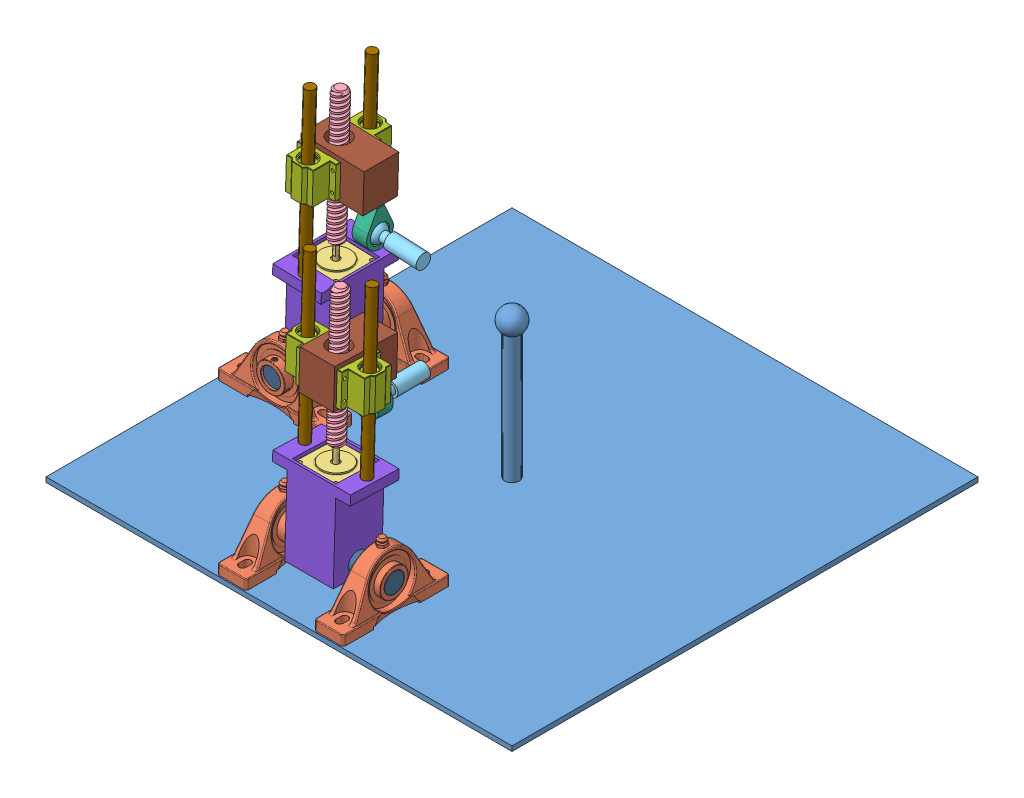
SolidWorks assembly vertical_Assem rev4, configuration Default. Lengths in mm.
Overall size (609.6 357.31 609.6).
28 component instances, 12 part files, 76 mates.
Components (placement in the parent):
- Bottom Platform rev2-1: Bottom Platform rev2 [Default] at origin size (609.6 200.03 609.6)
- 7728T560_MOUNTED BALL BEARING WITH CAST IRON HOUSING-1: 7728T560_MOUNTED BALL BEARING WITH CAST IRON HOUSING [7728T56] at (-63.5 42.8625 233.3625) x (0 0 -1) z (1 0 0) size (139.7 80.96 38.1)
- 7728T560_MOUNTED BALL BEARING WITH CAST IRON HOUSING-2: 7728T560_MOUNTED BALL BEARING WITH CAST IRON HOUSING [7728T56] at (-233.3625 42.8625 63.5) size (139.7 80.96 38.1)
- 7728T560_MOUNTED BALL BEARING WITH CAST IRON HOUSING-3: 7728T560_MOUNTED BALL BEARING WITH CAST IRON HOUSING [7728T56] at (-233.3625 42.8625 -63.5) size (139.7 80.96 38.1)
- 7728T560_MOUNTED BALL BEARING WITH CAST IRON HOUSING-4: 7728T560_MOUNTED BALL BEARING WITH CAST IRON HOUSING [7728T56] at (63.5 42.8625 233.3625) x (0 0 1) z (-1 0 0) size (139.7 80.96 38.1)
- 6627T540_POSITION-CONTROL DC MOTOR-2: 6627T540_POSITION-CONTROL DC MOTOR [6627T54] at (0 137.4326 230.4477) x (1 0 0) z (0 0.999525 -0.030807) size (57.15 58.17 99.31)
- 6627T540_POSITION-CONTROL DC MOTOR-3: 6627T540_POSITION-CONTROL DC MOTOR [6627T54] at (-230.4293 137.432 0) x (0 0 -1) z (0.031002 0.999519 0) size (57.15 58.17 99.31)
- 5966K221_BALL SCREW-3: 5966K221_BALL SCREW [5966K221] at (-229.7914 157.9961 0) x (0.970979 -0.030116 -0.237261) z (-0.031002 -0.999519 0) size (20.38 19.09 183.37)
- 5966K221_BALL SCREW-4: 5966K221_BALL SCREW [5966K221] at (0 157.9968 229.8138) x (0.271467 0.029651 0.961991) z (0 -0.999525 0.030807) size (20.38 19.09 183.37)
- top_Platform rev2-1: top_Platform rev2 [Default] at (0.7095 200.0079 0.2014) x (-0.999001 0.044698 -0.000225) z (-0.000791 -0.012664 0.999919) size (317.5 25.4 317.5) (hidden)
- ball-2: ball [Default] at (0.0499 185.85 116.2359) x (0.999641 -0.0268 0.000452) z (-0.026792 -0.999561 -0.01268) size (25.4 75.77 25.4)
- hole-1: hole [Default] at (0 258.8925 180.1999) x (0 0.030807 0.999525) z (1 0 0) size (19.05 91.29 35.03)
- ball-3: ball [Default] at (-115.947 192.5157 0.0142) x (0.040283 0.898119 -0.437904) z (0.019372 0.437476 0.899022) size (25.4 75.77 25.4)
- hole-2: hole [Default] at (-179.8387 269.1761 0) x (-0.999519 0.031002 0) z (0 0 1) size (19.05 91.29 35.03)
- 9338T100_MOUNTED LINEAR BALL BRNG-1: 9338T100_MOUNTED LINEAR BALL BRNG [9338T1] at (39.0525 243.1877 227.1881) x (0 -0.030807 -0.999525) z (0 0.999525 -0.030807) size (50.8 31.75 42.86)
- 9338T100_MOUNTED LINEAR BALL BRNG-2: 9338T100_MOUNTED LINEAR BALL BRNG [9338T1] at (-39.116 243.1887 227.2198) x (0 0.030807 0.999525) z (0 0.999525 -0.030807) size (50.8 31.75 42.86)
- 9338T100_MOUNTED LINEAR BALL BRNG-3: 9338T100_MOUNTED LINEAR BALL BRNG [9338T1] at (-226.8616 253.4814 -39.116) x (-0.999519 0.031002 0) z (0.031002 0.999519 0) size (50.8 31.75 42.86)
- 9338T100_MOUNTED LINEAR BALL BRNG-4: 9338T100_MOUNTED LINEAR BALL BRNG [9338T1] at (-226.8298 253.4804 39.0525) x (0.999519 -0.031002 0) z (0.031002 0.999519 0) size (50.8 31.75 42.86)
- motor mount-2: motor mount [Default] at (-265.5894 27.9794 -31.75) x (0 0 1) z (-0.999519 0.031002 0) size (101.6 114.3 63.5)
- motor mount-3: motor mount [Default] at (-31.75 27.9732 265.5865) x (1 0 0) z (0 0.030807 0.999525) size (101.6 114.3 63.5)
- linear bar-1: linear bar [Default] at (-230.8615 128.5512 -40.64) x (0.999519 -0.031002 0.000002) z (-0.000002 0 1) size (12.7 228.6 12.7)
- linear bar-2: linear bar [Default] at (40.64 128.5468 230.7215) x (-0.564697 -0.025425 -0.824906) z (0.825298 -0.017397 -0.564429) size (12.7 228.6 12.7)
- linear bar-3: linear bar [Default] at (-40.64 128.5516 230.8782) x (-0.912321 -0.012615 -0.409281) z (0.409475 -0.028106 -0.911888) size (12.7 228.6 12.7)
- linear bar-4: linear bar [Default] at (-230.7049 128.5463 40.64) x (0.951171 -0.029502 0.307253) z (-0.307105 0.009525 0.951628) size (12.7 228.6 12.7)
- horizontal bar-1: horizontal bar [Default] at (-79.375 42.8625 233.3625) size (158.75 25.4 25.4)
- horizontal bar-2: horizontal bar [Default] at (-233.3625 42.8625 -79.375) x (0 0 1) z (-1 0 0) size (158.75 25.4 25.4)
- screw_attach rev3-1: screw_attach rev3 [Default] at (-255.4169 228.9549 -23.241) x (0.999519 -0.031002 0) z (0 0 1) size (82.55 50.8 45.47)
- screw_attach rev3-2: screw_attach rev3 [Default] at (-23.241 218.6566 255.7704) x (0 -0.030807 -0.999525) z (1 0 0) size (82.55 50.8 45.47)
Mates (geometry in assembly coordinates):
- Coincident1: coincident anti-aligned: plane of Bottom Platform rev2-1 through (0 6.35 0) normal (0 1 0); plane of 7728T560_MOUNTED BALL BEARING WITH CAST IRON HOUSING-1 through (-44.45 6.35 203.2) normal (0 -1 0)
- Tangent3: tangent anti-aligned: cylinder of Bottom Platform rev2-1 through (-63.5 6.35 180.975) axis (0 1 0) radius 4.7625; plane of 7728T560_MOUNTED BALL BEARING WITH CAST IRON HOUSING-1 through (-58.7375 6.35 288.925) normal (-1 0 0)
- Tangent5: tangent anti-aligned: cylinder of Bottom Platform rev2-1 through (-63.5 6.35 285.75) axis (0 1 0) radius 4.7625; plane of 7728T560_MOUNTED BALL BEARING WITH CAST IRON HOUSING-1 through (-58.7375 6.35 288.925) normal (-1 0 0)
- Coincident3: coincident: cylinder of Bottom Platform rev2-1 through (-63.5 6.35 180.975) axis (0 1 0) radius 4.7625; moEndPointRef_w of 7728T560_MOUNTED BALL BEARING WITH CAST IRON HOUSING-1
- Coincident4: coincident anti-aligned: plane of Bottom Platform rev2-1 through (0 6.35 0) normal (0 1 0); plane of 7728T560_MOUNTED BALL BEARING WITH CAST IRON HOUSING-2 through (-303.2125 6.35 82.55) normal (0 -1 0)
- Coincident5: coincident anti-aligned: plane of Bottom Platform rev2-1 through (0 6.35 0) normal (0 1 0); plane of 7728T560_MOUNTED BALL BEARING WITH CAST IRON HOUSING-4 through (44.45 6.35 163.5125) normal (0 -1 0)
- Coincident6: coincident anti-aligned: plane of Bottom Platform rev2-1 through (0 6.35 0) normal (0 1 0); plane of 7728T560_MOUNTED BALL BEARING WITH CAST IRON HOUSING-3 through (-303.2125 6.35 -44.45) normal (0 -1 0)
- Tangent6: tangent anti-aligned: cylinder of Bottom Platform rev2-1 through (63.5 6.35 285.75) axis (0 1 0) radius 4.7625; plane of 7728T560_MOUNTED BALL BEARING WITH CAST IRON HOUSING-4 through (68.2625 6.35 282.575) normal (-1 0 0)
- Tangent7: tangent anti-aligned: cylinder of Bottom Platform rev2-1 through (63.5 6.35 180.975) axis (0 1 0) radius 4.7625; plane of 7728T560_MOUNTED BALL BEARING WITH CAST IRON HOUSING-4 through (68.2625 6.35 177.8) normal (-1 0 0)
- Coincident7: coincident: cylinder of Bottom Platform rev2-1 through (63.5 6.35 180.975) axis (0 1 0) radius 4.7625; moEndPointRef_w of 7728T560_MOUNTED BALL BEARING WITH CAST IRON HOUSING-4
- Tangent8: tangent anti-aligned: cylinder of Bottom Platform rev2-1 through (-180.975 6.35 63.5) axis (0 1 0) radius 4.7625; plane of 7728T560_MOUNTED BALL BEARING WITH CAST IRON HOUSING-2 through (-184.15 6.35 58.7375) normal (0 0 1)
- Tangent9: tangent anti-aligned: cylinder of Bottom Platform rev2-1 through (-285.75 6.35 63.5) axis (0 1 0) radius 4.7625; plane of 7728T560_MOUNTED BALL BEARING WITH CAST IRON HOUSING-2 through (-288.925 6.35 58.7375) normal (0 0 1)
- Coincident8: coincident: cylinder of Bottom Platform rev2-1 through (-180.975 6.35 63.5) axis (0 1 0) radius 4.7625; moEndPointRef_w of 7728T560_MOUNTED BALL BEARING WITH CAST IRON HOUSING-2
- Tangent10: tangent anti-aligned: cylinder of Bottom Platform rev2-1 through (-180.975 6.35 -63.5) axis (0 1 0) radius 4.7625; plane of 7728T560_MOUNTED BALL BEARING WITH CAST IRON HOUSING-3 through (-184.15 6.35 -68.2625) normal (0 0 1)
- Tangent11: tangent anti-aligned: cylinder of Bottom Platform rev2-1 through (-285.75 6.35 -63.5) axis (0 1 0) radius 4.7625; plane of 7728T560_MOUNTED BALL BEARING WITH CAST IRON HOUSING-3 through (-288.925 6.35 -68.2625) normal (0 0 1)
- Coincident9: coincident: cylinder of Bottom Platform rev2-1 through (-285.75 6.35 -63.5) axis (0 1 0) radius 4.7625; moEndPointRef_w of 7728T560_MOUNTED BALL BEARING WITH CAST IRON HOUSING-3
- Coincident12: coincident: moEndPointRef_w of 6627T540_POSITION-CONTROL DC MOTOR-3; plane of assembly
- Coincident13: coincident: moEndPointRef_w of 6627T540_POSITION-CONTROL DC MOTOR-2; plane of assembly
- Coincident16: coincident anti-aligned: plane of 6627T540_POSITION-CONTROL DC MOTOR-3 through (-232.9649 158.0946 0) normal (0.031002 0.999519 0); plane of 5966K221_BALL SCREW-3 through (-229.7914 157.9961 0) normal (-0.031002 -0.999519 0)
- Concentric5: concentric anti-aligned: cylinder of 6627T540_POSITION-CONTROL DC MOTOR-3 through (-229.7914 157.9961 0) axis (0.031002 0.999519 0) radius 3.175; cylinder of 5966K221_BALL SCREW-3 through (-224.2793 335.7107 0) axis (-0.031002 -0.999519 0) radius 9.525
- Concentric6: concentric anti-aligned: cylinder of 6627T540_POSITION-CONTROL DC MOTOR-2 through (0 157.9968 229.8138) axis (0 0.999525 -0.030807) radius 3.175; cylinder of 5966K221_BALL SCREW-4 through (0 335.7124 224.3363) axis (0 -0.999525 0.030807) radius 9.525
- Coincident17: coincident anti-aligned: plane of 6627T540_POSITION-CONTROL DC MOTOR-2 through (0 157.899 226.6403) normal (0 0.999525 -0.030807); plane of 5966K221_BALL SCREW-4 through (0 157.9968 229.8138) normal (0 -0.999525 0.030807)
- Concentric18: concentric anti-aligned: cylinder of top_Platform rev2-1 through (0.0162 185.3112 158.7775) axis (-0.000791 -0.012664 0.999919) radius 9.525; cylinder of ball-2 through (0.0162 185.3112 158.7775) axis (0.000791 0.012664 -0.999919) radius 9.525
- Coincident31: coincident aligned: circle of top_Platform rev2-1; circle of ball-2
- Tangent12: tangent aligned: sphere of ball-2; cylinder of hole-1 through (0 184.8557 172.9524) axis (0 0.030807 0.999525) radius 12.7
- Concentric20: concentric anti-aligned: cylinder of top_Platform rev2-1 through (-158.4494 194.4173 0.0046) axis (-0.999001 0.044698 -0.000225) radius 9.525; cylinder of ball-3 through (-158.4494 194.4173 0.0046) axis (0.999001 -0.044698 0.000225) radius 9.525
- Coincident35: coincident aligned: plane of top_Platform rev2-1 through (-159.1427 179.7207 158.5807) normal (-0.999001 0.044698 -0.000225); plane of ball-3 through (-158.4494 194.4173 0.0046) normal (-0.999001 0.044698 -0.000225)
- Tangent13: tangent aligned: sphere of ball-3; cylinder of hole-2 through (-172.6055 195.1378 0) axis (-0.999519 0.031002 0) radius 12.7
- Parallel5: parallel anti-aligned: plane of Bottom Platform rev2-1 through (0 6.35 0) normal (0 1 0); plane of top_Platform rev2-1
- Tangent16: tangent aligned: sphere of Bottom Platform rev2-1; cylinder of top_Platform rev2-1 through (-0.4257 174.6353 -0.1208) axis (0.044691 0.99892 0.012687) radius 15.875
- Tangent18: tangent aligned: sphere of Bottom Platform rev2-1; plane of top_Platform rev2-1 through (0.7095 200.0079 0.2014) normal (0.044691 0.99892 0.012687)
- Coincident50: coincident anti-aligned: plane of 6627T540_POSITION-CONTROL DC MOTOR-3 through (-217.79 58.2621 25.019) normal (-0.031002 -0.999519 0); plane of motor mount-2 through (-264.6051 59.7142 -31.75) normal (0.031002 0.999519 0)
- Coincident51: coincident anti-aligned: plane of 6627T540_POSITION-CONTROL DC MOTOR-3 through (-205.199 131.567 -28.575) normal (0 0 -1); plane of motor mount-2 through (-258.8724 142.1261 -28.575) normal (0 0 1)
- Coincident52: coincident anti-aligned: plane of 6627T540_POSITION-CONTROL DC MOTOR-3 through (-259.148 133.2403 -25.4) normal (-0.999519 0.031002 0); plane of motor mount-2 through (-258.8724 142.1261 -28.575) normal (0.999519 -0.031002 0)
- Coincident53: coincident anti-aligned: plane of 6627T540_POSITION-CONTROL DC MOTOR-2 through (-25.019 59.1948 247.9539) normal (0 -0.999525 0.030807); plane of motor mount-3 through (-31.75 59.7081 264.6084) normal (0 0.999525 -0.030807)
- Coincident54: coincident anti-aligned: plane of 6627T540_POSITION-CONTROL DC MOTOR-2 through (25.4 131.4747 202.0427) normal (0 -0.030807 -0.999525); plane of motor mount-3 through (-28.575 140.3605 201.7688) normal (0 0.030807 0.999525)
- Coincident55: coincident anti-aligned: plane of 6627T540_POSITION-CONTROL DC MOTOR-2 through (28.575 133.1375 255.9921) normal (1 0 0); plane of motor mount-3 through (28.575 142.1211 258.8917) normal (-1 0 0)
- Coincident56: coincident aligned: plane of motor mount-2 through (-262.4396 129.5306 -50.8) normal (-0.031002 -0.999519 0); plane of linear bar-1 through (-230.8615 128.5512 -40.64) normal (-0.031002 -0.999519 0)
- Concentric43: concentric anti-aligned: cylinder of motor mount-2 through (-230.4678 141.245 -40.64) axis (0.031002 0.999519 0) radius 6.35; cylinder of linear bar-1 through (-223.7745 357.0413 -40.64) axis (-0.031002 -0.999519 0) radius 6.35
- Concentric44: concentric anti-aligned: cylinder of motor mount-2 through (-230.3112 141.2402 40.64) axis (0.031002 0.999519 0) radius 6.35; cylinder of linear bar-4 through (-223.6179 357.0364 40.64) axis (-0.031002 -0.999519 0) radius 6.35
- Coincident57: coincident aligned: plane of motor mount-2 through (-262.4396 129.5306 50.8) normal (-0.031002 -0.999519 0); plane of linear bar-4 through (-230.7049 128.5463 40.64) normal (-0.031002 -0.999519 0)
- Concentric45: concentric anti-aligned: cylinder of motor mount-3 through (-40.64 141.2456 230.4869) axis (0 0.999525 -0.030807) radius 6.35; cylinder of linear bar-3 through (-40.64 357.0431 223.8356) axis (0 -0.999525 0.030807) radius 6.35
- Concentric46: concentric anti-aligned: cylinder of motor mount-3 through (40.64 141.2408 230.3303) axis (0 0.999525 -0.030807) radius 6.35; cylinder of linear bar-2 through (40.64 357.0383 223.679) axis (0 -0.999525 0.030807) radius 6.35
- Coincident58: coincident aligned: plane of motor mount-3 through (-50.8 129.5249 262.4565) normal (0 -0.999525 0.030807); plane of linear bar-3 through (-40.64 128.5516 230.8782) normal (0 -0.999525 0.030807)
- Coincident59: coincident aligned: plane of motor mount-3 through (50.8 129.5249 262.4565) normal (0 -0.999525 0.030807); plane of linear bar-2 through (40.64 128.5468 230.7215) normal (0 -0.999525 0.030807)
- Concentric47: concentric anti-aligned: cylinder of 9338T100_MOUNTED LINEAR BALL BRNG-1 through (40.64 221.7666 227.8483) axis (0 0.999525 -0.030807) radius 6.35; cylinder of linear bar-2 through (40.64 357.0383 223.679) axis (0 -0.999525 0.030807) radius 6.35
- Concentric48: concentric anti-aligned: cylinder of 9338T100_MOUNTED LINEAR BALL BRNG-4 through (-227.4943 232.0594 40.64) axis (0.031002 0.999519 0) radius 6.35; cylinder of linear bar-4 through (-223.6179 357.0364 40.64) axis (-0.031002 -0.999519 0) radius 6.35
- Coincident60: coincident aligned: plane of 7728T560_MOUNTED BALL BEARING WITH CAST IRON HOUSING-1 through (-79.375 42.8625 233.3625) normal (-1 0 0); plane of horizontal bar-1 through (-79.375 42.8625 233.3625) normal (-1 0 0)
- Concentric51: concentric anti-aligned: cylinder of 7728T560_MOUNTED BALL BEARING WITH CAST IRON HOUSING-1 through (-79.375 42.8625 233.3625) axis (1 0 0) radius 12.7025; cylinder of horizontal bar-1 through (79.375 42.8625 233.3625) axis (-1 0 0) radius 12.7
- Coincident61: coincident aligned: plane of 7728T560_MOUNTED BALL BEARING WITH CAST IRON HOUSING-3 through (-233.3625 42.8625 -79.375) normal (0 0 -1); plane of horizontal bar-2 through (-233.3625 42.8625 -79.375) normal (0 0 -1)
- Concentric52: concentric anti-aligned: cylinder of 7728T560_MOUNTED BALL BEARING WITH CAST IRON HOUSING-3 through (-233.3625 42.8625 -79.375) axis (0 0 1) radius 12.7025; cylinder of horizontal bar-2 through (-233.3625 42.8625 79.375) axis (0 0 -1) radius 12.7
- Concentric54: concentric anti-aligned: cylinder of motor mount-2 through (-233.3625 42.8625 31.75) axis (0 0 1) radius 12.7; cylinder of horizontal bar-2 through (-233.3625 42.8625 79.375) axis (0 0 -1) radius 12.7
- Concentric56: concentric anti-aligned: cylinder of motor mount-3 through (31.75 42.8625 233.3625) axis (1 0 0) radius 12.7; cylinder of horizontal bar-1 through (79.375 42.8625 233.3625) axis (-1 0 0) radius 12.7
- Screw1: screw = 25.4 mm anti-aligned: cylinder of 5966K221_BALL SCREW-3 through (-224.2793 335.7107 0) axis (-0.031002 -0.999519 0) radius 9.525; cylinder of screw_attach rev3-1 through (-227.6173 228.0926 0) axis (0.031002 0.999519 0) radius 14
- Coincident62: coincident anti-aligned: plane of 9338T100_MOUNTED LINEAR BALL BRNG-3 through (-200.8094 274.1149 -23.241) normal (0 0 1); plane of screw_attach rev3-1 through (-255.4169 228.9549 -23.241) normal (0 0 -1)
- Concentric59: concentric anti-aligned: cylinder of 9338T100_MOUNTED LINEAR BALL BRNG-3 through (-205.0469 265.5109 -35.2037) axis (0 0 1) radius 1.9844; cylinder of screw_attach rev3-1 through (-205.0469 265.5109 -23.241) axis (0 0 -1) radius 1.9844
- Concentric60: concentric anti-aligned: cylinder of 9338T100_MOUNTED LINEAR BALL BRNG-3 through (-247.8888 266.8397 -35.2037) axis (0 0 1) radius 1.9844; cylinder of screw_attach rev3-1 through (-247.8888 266.8397 -23.241) axis (0 0 -1) radius 1.9844
- Parallel10: parallel aligned: plane of motor mount-2 through (-264.6051 59.7142 -31.75) normal (-0.999519 0.031002 0); plane of screw_attach rev3-1 through (-255.4169 228.9549 22.225) normal (-0.999519 0.031002 0)
- Parallel12: parallel anti-aligned: plane of 9338T100_MOUNTED LINEAR BALL BRNG-4 through (-251.5532 275.6888 23.1775) normal (0 0 -1); plane of screw_attach rev3-1 through (-255.4169 228.9549 22.225) normal (0 0 1)
- Screw2: screw = 25.4 mm anti-aligned: cylinder of 5966K221_BALL SCREW-4 through (0 335.7124 224.3363) axis (0 -0.999525 0.030807) radius 9.525; cylinder of screw_attach rev3-2 through (0 217.7997 227.9706) axis (0 0.999525 -0.030807) radius 14
- Parallel15: parallel aligned: plane of motor mount-3 through (-31.75 59.7081 264.6084) normal (0 0.030807 0.999525); plane of screw_attach rev3-2 through (22.225 218.6566 255.7704) normal (0 0.030807 0.999525)
- Parallel19: parallel anti-aligned: plane of 9338T100_MOUNTED LINEAR BALL BRNG-1 through (23.1775 263.8262 201.1399) normal (-1 0 0); plane of screw_attach rev3-2 through (22.225 218.6566 255.7704) normal (1 0 0)
- Parallel21: parallel aligned: plane of hole-1 through (0 185.4425 191.9933) normal (0 0.030807 0.999525); plane of motor mount-3 through (-31.75 59.7081 264.6084) normal (0 0.030807 0.999525)
- Tangent24: tangent aligned: sphere of ball-2; plane of hole-1 through (0 185.4425 191.9933) normal (0 0.030807 0.999525)
- Concentric78: concentric anti-aligned: cylinder of hole-2 through (-181.1576 226.6516 0) axis (0.031002 0.999519 0) radius 4.7625; cylinder of screw_attach rev3-1 through (-181.1576 226.6516 0) axis (-0.031002 -0.999519 0) radius 4.2164
- Coincident76: coincident anti-aligned: plane of hole-2 through (-171.6372 226.3563 4.7625) normal (0.031002 0.999519 0); plane of screw_attach rev3-1 through (-172.9066 226.3957 22.225) normal (-0.031002 -0.999519 0)
- Parallel22: parallel aligned: plane of hole-2 through (-191.6463 195.7284 0) normal (-0.999519 0.031002 0); plane of motor mount-2 through (-264.6051 59.7142 -31.75) normal (-0.999519 0.031002 0)
- Tangent25: tangent aligned: sphere of ball-3; plane of hole-2 through (-191.6463 195.7284 0) normal (-0.999519 0.031002 0)
- Concentric79: concentric anti-aligned: cylinder of hole-1 through (0 216.3677 181.5106) axis (0 0.999525 -0.030807) radius 4.7625; cylinder of screw_attach rev3-2 through (0 216.3677 181.5106) axis (0 -0.999525 0.030807) radius 4.2164
- Coincident78: coincident anti-aligned: plane of hole-1 through (4.7625 216.0743 171.9902) normal (0 0.999525 -0.030807); plane of screw_attach rev3-2 through (22.225 216.1134 173.2596) normal (0 -0.999525 0.030807)
- Concentric84: concentric anti-aligned: cylinder of 9338T100_MOUNTED LINEAR BALL BRNG-2 through (-35.2037 256.5429 248.2496) axis (1 0 0) radius 1.9844; cylinder of screw_attach rev3-2 through (-23.241 256.5429 248.2496) axis (-1 0 0) radius 1.9844
- Concentric85: concentric anti-aligned: cylinder of 9338T100_MOUNTED LINEAR BALL BRNG-2 through (-35.2037 231.1549 249.0321) axis (1 0 0) radius 1.9844; cylinder of screw_attach rev3-2 through (-23.241 231.1549 249.0321) axis (-1 0 0) radius 1.9844
- Coincident79: coincident anti-aligned: plane of 9338T100_MOUNTED LINEAR BALL BRNG-2 through (-23.241 263.8272 201.1716) normal (1 0 0); plane of screw_attach rev3-2 through (-23.241 218.6566 255.7704) normal (-1 0 0)
- Coincident80: coincident aligned: plane of 9338T100_MOUNTED LINEAR BALL BRNG-1 through (29.5275 265.3913 251.9158) normal (0 0.999525 -0.030807); plane of 9338T100_MOUNTED LINEAR BALL BRNG-2 through (-29.591 263.8272 201.1716) normal (0 0.999525 -0.030807)
- Coincident81: coincident aligned: plane of 9338T100_MOUNTED LINEAR BALL BRNG-3 through (-200.8094 274.1149 -29.591) normal (0.031002 0.999519 0); plane of 9338T100_MOUNTED LINEAR BALL BRNG-4 through (-251.5532 275.6888 29.5275) normal (0.031002 0.999519 0)
- LimitDistance1: limit distance = 76.5953 mm anti-aligned: plane of motor mount-3 through (-31.75 142.2189 262.0652) normal (0 0.999525 -0.030807); plane of screw_attach rev3-2 through (22.225 216.1134 173.2596) normal (0 -0.999525 0.030807)
